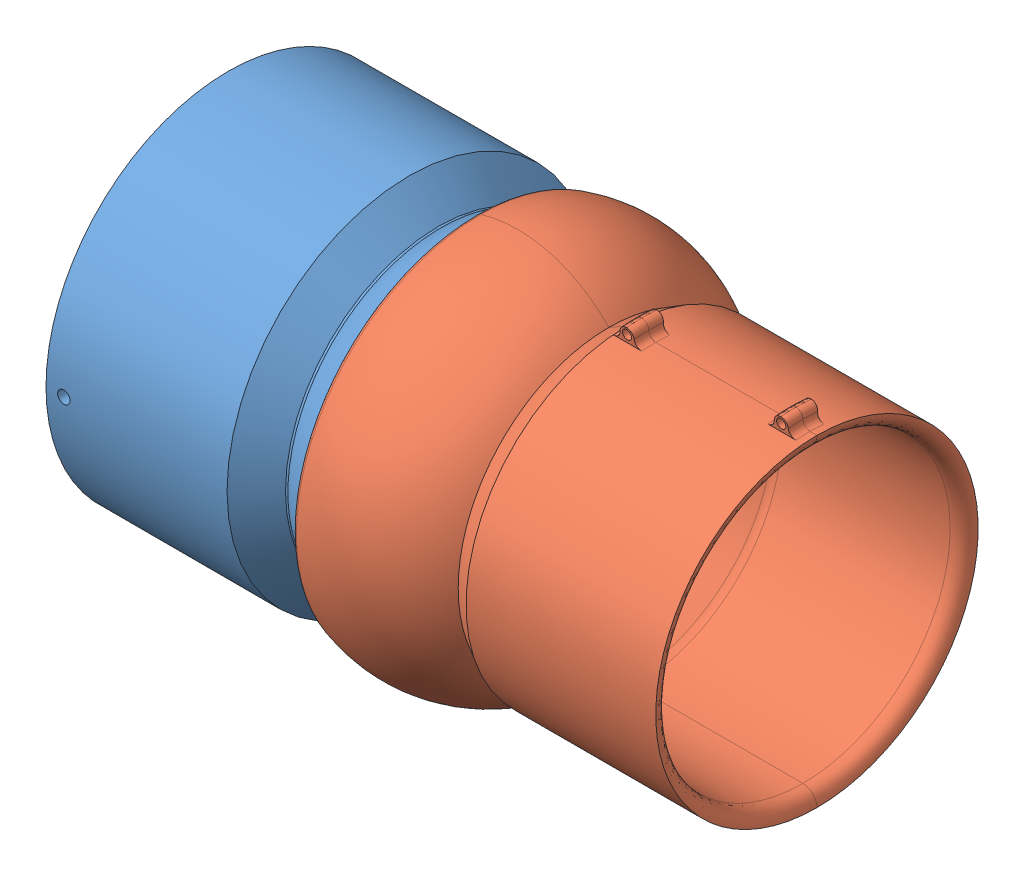
SolidWorks assembly V3_Gimbal Duct_TVR_UBC Rocket, configuration Default. Lengths in mm.
Overall size (210 135.56 135.56).
3 component instances, 2 part files, 4 mates.
Components (placement in the parent):
- V3_Upper Gimbal Nozzle-1: V3_Upper Gimbal Nozzle [Default] at (55.0908 102.2421 83.5033) size (135 130 130)
- V3.2_Lower Gimbal Nozzle-1: V3.2_Lower Gimbal Nozzle [Default] at (115.0908 102.2421 83.5033) x (-1 0 0) z (0 0 1) size (121.66 135.56 68.28)
- V3.2_Lower Gimbal Nozzle-2: V3.2_Lower Gimbal Nozzle [Default] at (115.0908 102.2421 83.5033) x (-1 0 0) z (0 0 -1) size (121.66 135.56 68.28)
Mates (geometry in assembly coordinates):
- Coincident1: coincident anti-aligned: circle of V3_Upper Gimbal Nozzle-1; circle of V3.2_Lower Gimbal Nozzle-1
- Coincident2: coincident anti-aligned: circle of V3_Upper Gimbal Nozzle-1; circle of V3.2_Lower Gimbal Nozzle-2
- Coincident3: coincident anti-aligned: plane of V3.2_Lower Gimbal Nozzle-1 through (83.3099 79.0316 83.5033) normal (0 0 1); plane of V3.2_Lower Gimbal Nozzle-2 through (83.3099 79.0316 83.5033) normal (0 0 -1)
- Parallel1: parallel anti-aligned: plane of V3.2_Lower Gimbal Nozzle-2 through (83.3099 79.0316 83.5033) normal (0 0 -1)
